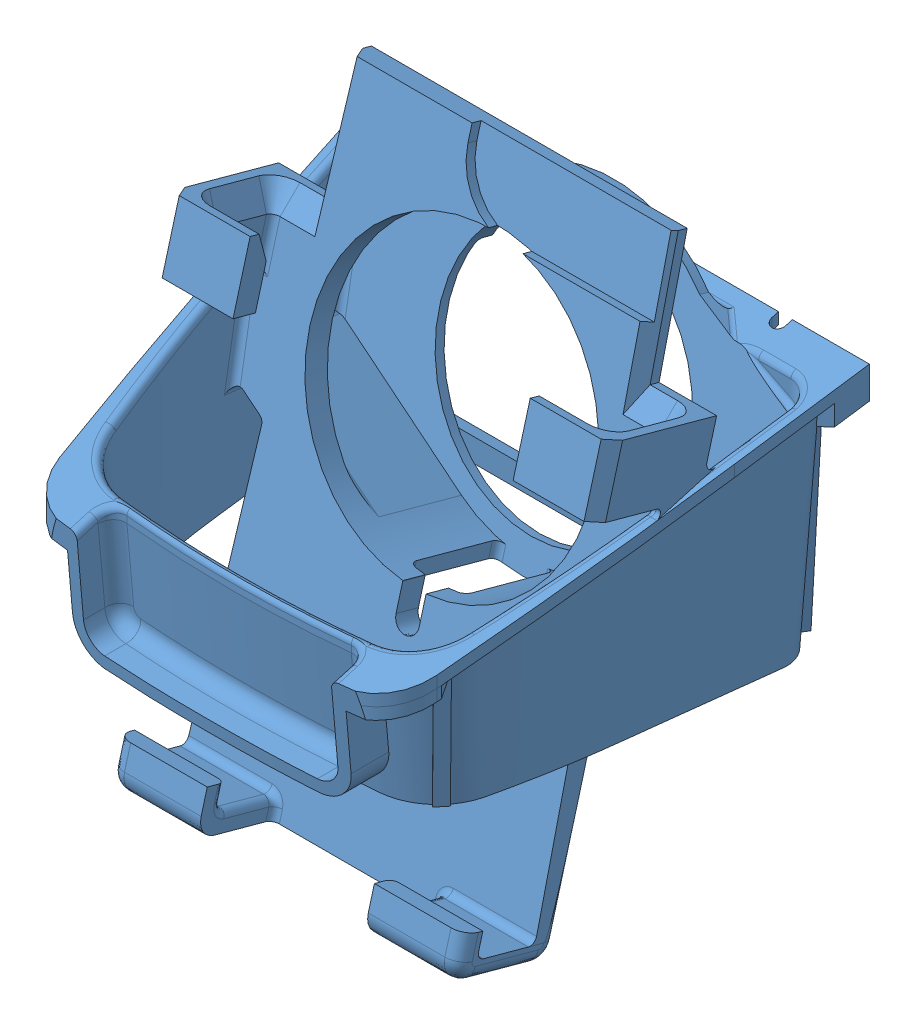
SolidWorks assembly PhoneStand, configuration 默认. Lengths in mm.
Overall size (105 119.43 92.96).
7 component instances, 7 part files, 22 mates.
Components (placement in the parent):
- PhoneStand-1: PhoneStand [默认] at origin size (105 95.05 92.96) (hidden)
- inside-1: inside [默认] at origin size (100.97 89.93 79.4) (hidden)
- ChargerStand-1: ChargerStand [默认] at (0 77.9773 32.6392) x (1 0 0) z (0 0.263562 0.964642) size (141.21 123.38 46) (hidden)
- CoolerCharge-1: CoolerCharge [默认] at (0 79.3116 37.5231) x (-1 0 0) z (0 -0.964642 0.263562) size (61.2 25.5 70.6) (hidden)
- iPhone13Pro_WithShell-1: iPhone13Pro_WithShell [默认] at (0 80.1941 37.5278) x (1 0 0) z (0 -0.964642 0.263562) size (75.1 13.5 150.3) (hidden)
- 零件3^PhoneStand-1: 零件3^PhoneStand [默认] at origin size (101.41 119.43 71.02) (hidden, virtual)
- 零件4^PhoneStand-1: 零件4^PhoneStand [默认] at origin size (105 119.43 92.96) (virtual)
Mates (geometry in assembly coordinates):
- 重合1: coordinate: point of PhoneStand-1
- 平行1: parallel anti-aligned: line of PhoneStand-1 through (105 -52.5 95) axis (0 1 0); line of iPhoneX_WithShell-1 through (27 155.5691 33.9122) axis (-1 0 0)
- 重合3: coincident: plane of PhoneStand-1 through (0 0 0) normal (1 0 0)
- 平行2: parallel aligned: line of 零件5^PhoneStand-1 through (105 -52.5 95) axis (0 1 0); line of ChargerStand-1 through (-34 126.5073 23.6238) axis (1 0 0)
- 同心1: concentric anti-aligned: circle of iPhoneX_WithShell-1; circle of ChargerStand-1
- 重合5: coincident: line of ChargerStand-1 through (0 121.466 20.7571) axis (0 -0.964642 0.263562)
- 距离1: distance = 0.3 mm anti-aligned: plane of iPhoneX_WithShell-1 through (0 154.9758 29.9564) normal (0 -0.148306 -0.988942); plane of ChargerStand-1 through (0 79.2951 37.4624) normal (0 0.263562 0.964642)
- 重合9: coincident: line of 零件5^PhoneStand-1 through (105 -52.5 95) axis (0 1 0); plane of ChargerStand-1 through (0 81.9231 30.3099) normal (0 -0.148306 -0.988942)
- 重合10: coincident: plane of 零件5^PhoneStand-1 through (27.1126 3.5 50.7877) normal (0 1 0); line of ChargerStand-1 through (-16.5 3.7636 58.0993) axis (1 0 0)
- 重合11: coordinate: unknown of 零件1^PhoneStand-1
- 同心2: concentric aligned: circle of iPhoneX_WithShell-1; circle of CoolerCharge-1
- 重合13: coincident anti-aligned: plane of iPhoneX_WithShell-1 through (0 154.9758 29.9564) normal (0 -0.148306 -0.988942); plane of CoolerCharge-1 through (0 79.3116 37.5231) normal (0 0.263562 0.964642)
- 重合15: coincident: plane of inside-1 through (27.1126 3.5 50.7877) normal (0 -1 0); line of ChargerStand-1 through (-34.5 3.5 57.1347) axis (1 0 0)
- 重合16: coincident: line of ChargerStand-1 through (0 121.466 20.7571) axis (0 -0.964642 0.263562)
- 垂直1: perpendicular: line of ChargerStand-1 through (-34.5 3.5 57.1347) axis (1 0 0)
- 垂直2: perpendicular: line of CoolerCharge-1 through (16.9148 48.9149 23.0218) axis (-1 0 0)
- 重合19: coincident aligned: cone of CoolerCharge-1 through (0 72.9861 14.3717) axis (0 -0.263562 -0.964642); cone of Intack-1 through (-8.6216 77.9719 -50.9242) axis (0 -0.148306 -0.988942)
- 距离2: distance = 0.3 mm anti-aligned: plane of iPhone13Pro_WithShell-1 through (0 80.1941 37.5278) normal (0 -0.263562 -0.964642); plane of ChargerStand-1 through (0 79.2951 37.4624) normal (0 0.263562 0.964642)
- 重合21: coincident anti-aligned: plane of ChargerStand-1 through (37.5 12.1027 73.444) normal (0 0.964642 -0.263562); plane of iPhone13Pro_WithShell-1 through (37.55 10.6004 67.9456) normal (0 -0.964642 0.263562)
- 重合26: coincident: line of iPhone13Pro_WithShell-1 through (0 150.2917 15.7839) axis (0 -0.964642 0.263562)
- 重合28: coincident: line of inside-1 through (43.486 92.7428 7.8719) axis (-1 0 0); plane of ChargerStand-1 through (0 72.706 13.3464) normal (0 0.263562 0.964642)
- 同心3: concentric anti-aligned: circle of CoolerCharge-1; circle of 零件4^PhoneStand-1
